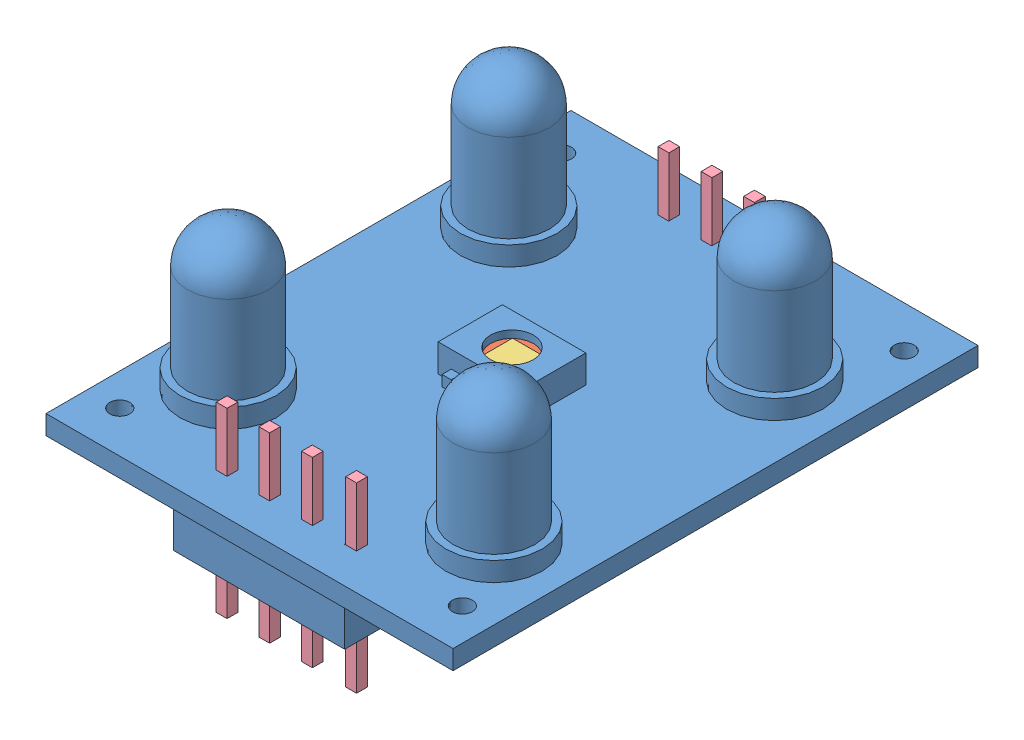
SolidWorks assembly arduino_topboard2, configuration Default. Lengths in mm.
Overall size (100.85 16.07 222.25).
11 component instances, 4 part files, 3 mates.
Components (placement in the parent):
- arduino_board-1: arduino_board [Default] at (6.2353 15.8719 29.0967) x (0 1 0) z (1 0 0) size (12.58 31.12 24.13)
- arduino_top2-2: arduino_top2 [Default] at (6.2353 17.0852 29.0967) size (2.54 1.14 2.54)
- arduino_top3-2: arduino_top3 [Default] at (6.2353 17.0994 29.0675) size (1.76 1.14 1.76)
- metal-5: metal [Default] at (10.1129 20.5069 42.19) x (0 -1 0) z (1 0 0) size (10.8 0.64 0.64)
- metal-6: metal [Default] at (7.4942 9.7069 42.19) x (0 1 0) z (0 0 1) size (10.8 0.64 0.64)
- metal-7: metal [Default] at (4.9672 9.7069 42.1966) x (0 1 0) z (0 0 1) size (10.8 0.64 0.64)
- metal-8: metal [Default] at (2.4422 9.7069 42.1966) x (0 1 0) z (0 0 1) size (10.8 0.64 0.64)
- metal-9: metal [Default] at (4.9774 9.7069 15.9854) x (0 1 0) z (0 0 1) size (10.8 0.64 0.64)
- metal-10: metal [Default] at (2.4248 9.7069 15.9854) x (0 1 0) z (0 0 1) size (10.8 0.64 0.64)
- metal-11: metal [Default] at (7.5138 9.7069 16.0016) x (0 1 0) z (0 0 1) size (10.8 0.64 0.64)
- metal-12: metal [Default] at (10.0664 9.7069 16.0179) x (0 1 0) z (0 0 1) size (10.8 0.64 0.64)
Mates (geometry in assembly coordinates):
- Parallel6: parallel aligned: plane of arduino_board-1 through (6.2353 17.0119 29.0967) normal (0 1 0); plane of arduino_top3-2 through (6.2353 18.2394 29.0675) normal (0 1 0)
- Concentric1: concentric anti-aligned: circle of arduino_board-1; cylinder of arduino_top2-2 through (6.2353 18.2252 29.0967) axis (0 -1 0) radius 1.27
- Coincident26: coincident anti-aligned: plane of arduino_top2-2 through (5.3553 17.0852 29.9767) normal (1 0 0); plane of arduino_top3-2 through (5.3553 18.2394 28.1875) normal (-1 0 0)
